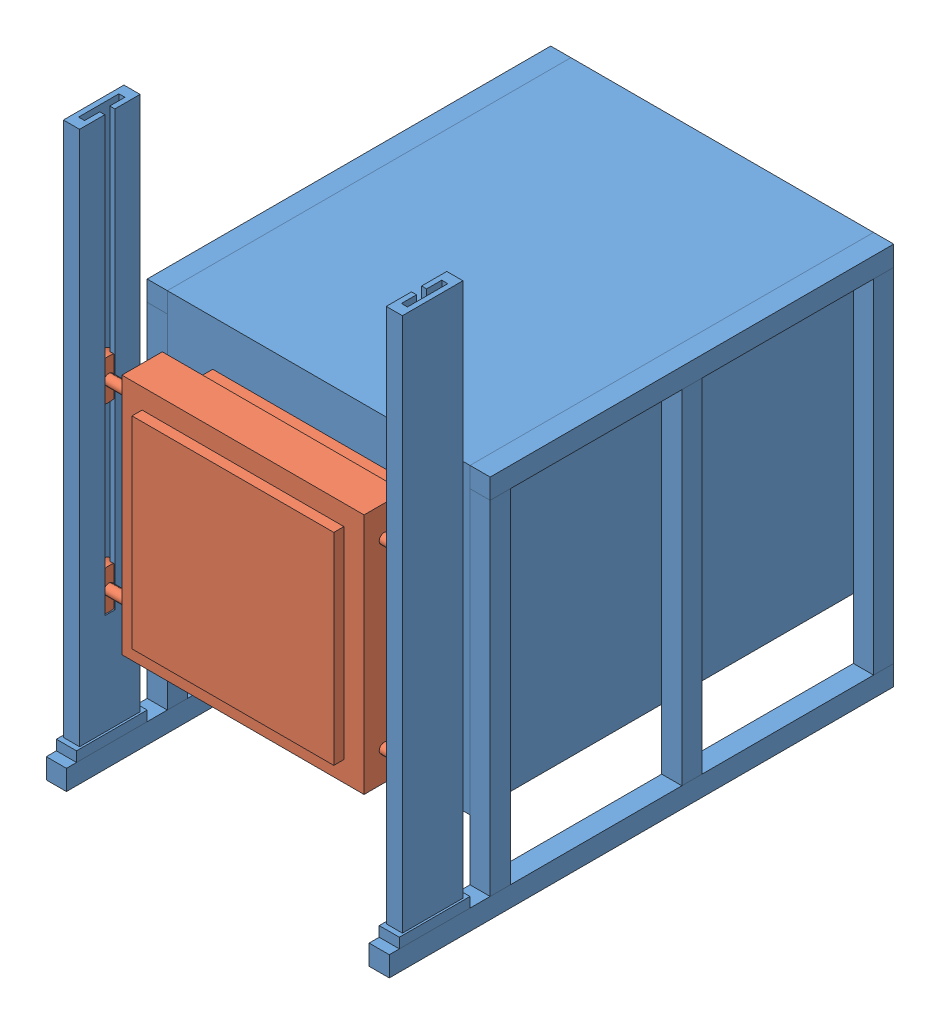
SolidWorks assembly Сборка2, configuration По умолчанию. Lengths in mm.
Overall size (1700 2800 2500).
2 component instances, 2 part files, 4 mates.
Components (placement in the parent):
- Корпус печи-1: Корпус печи [По умолчанию] at (11.869 94.6114 2800) size (1700 2800 2500)
- Крышка печи-1: Крышка печи [По умолчанию] at (11.869 144.6114 2800) size (1630 1200 425)
Mates (geometry in assembly coordinates):
- Совпадение1: coincident anti-aligned: plane of Корпус печи-1 through (11.869 94.6114 2800) normal (0 0 1); plane of Крышка печи-1 through (11.869 144.6114 2800) normal (0 0 -1)
- Совпадение2: coincident anti-aligned: plane of Корпус печи-1 through (-803.131 1744.6114 2800) normal (1 0 0); plane of Крышка печи-1 through (-803.131 144.6114 2800) normal (-1 0 0)
- Касательность1: tangent anti-aligned: plane of Корпус печи-1 through (11.869 1744.6114 2975) normal (0 0 1); cylinder of Крышка печи-1 through (-753.131 594.6114 3075) axis (-1 0 0) radius 100
- Граничное расстояние1: limit distance = 1000 mm aligned: plane of Крышка печи-1 through (-588.131 744.6114 3175) normal (0 1 0); plane of Корпус печи-1 through (11.869 1744.6114 2800) normal (0 1 0)
